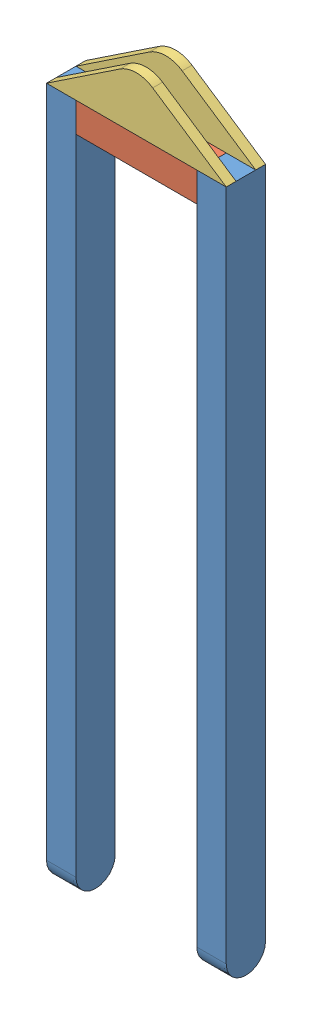
SolidWorks assembly stelaz spaw, configuration Domyślna. Lengths in mm.
Overall size (183 755 40).
5 component instances, 3 part files, 12 mates.
Components (placement in the parent):
- belka długa-1: belka długa [Domyślna] at (-439.7874 -5.7608 685) x (0 0 1) z (-1 0 0) size (40 700 30)
- belka długa-2: belka długa [Domyślna] at (-622.7874 -5.7608 725) x (0 0 -1) z (1 0 0) size (40 700 30)
- belka krótka-1: belka krótka [Domyślna] at (-592.7874 -35.7608 685) size (123 30 40)
- ucho stelaza-1: ucho stelaza [Domyślna] at (-622.7874 -5.7608 715) size (183 55 10)
- ucho stelaza-2: ucho stelaza [Domyślna] at (-622.7874 -5.7608 685) size (183 55 10)
Mates (geometry in assembly coordinates):
- Wspólnie13: coincident anti-aligned: plane of belka długa-2 through (-592.7874 -685.7608 705) normal (1 0 0); plane of belka krótka-1 through (-592.7874 -35.7608 725) normal (-1 0 0)
- Wspólnie14: coincident aligned: plane of belka długa-2 through (-592.7874 -5.7608 725) normal (0 0 1); plane of belka krótka-1 through (-592.7874 -35.7608 725) normal (0 0 1)
- Wspólnie15: coincident aligned: plane of belka długa-2 through (-592.7874 -5.7608 725) normal (0 1 0); plane of belka krótka-1 through (-592.7874 -5.7608 725) normal (0 1 0)
- Wspólnie16: coincident anti-aligned: plane of belka długa-1 through (-469.7874 -685.7608 705) normal (-1 0 0); plane of belka krótka-1 through (-469.7874 -35.7608 725) normal (1 0 0)
- Wspólnie17: coincident aligned: plane of belka długa-1 through (-469.7874 -5.7608 725) normal (0 0 1); plane of belka krótka-1 through (-592.7874 -35.7608 725) normal (0 0 1)
- Wspólnie18: coincident aligned: plane of belka długa-1 through (-469.7874 -5.7608 685) normal (0 1 0); plane of belka krótka-1 through (-592.7874 -5.7608 725) normal (0 1 0)
- Wspólnie20: coincident aligned: plane of belka krótka-1 through (-592.7874 -35.7608 725) normal (0 0 1); plane of ucho stelaza-1 through (-531.2874 19.2392 725) normal (0 0 1)
- Wspólnie22: coincident anti-aligned: plane of belka krótka-1 through (-592.7874 -5.7608 725) normal (0 1 0); plane of ucho stelaza-1 through (-622.7874 -5.7608 725) normal (0 -1 0)
- Wspólnie23: coincident anti-aligned: line of belka długa-2 through (-622.7874 -5.7608 685) axis (0 0 1); line of ucho stelaza-1 through (-622.7874 -5.7608 725) axis (0 0 -1)
- Wspólnie24: coincident: line of belka krótka-1 through (-469.7874 -5.7608 685) axis (-1 0 0); plane of ucho stelaza-2 through (-531.2874 19.2392 685) normal (0 0 -1)
- Wspólnie25: coincident anti-aligned: plane of belka krótka-1 through (-592.7874 -5.7608 725) normal (0 1 0); plane of ucho stelaza-2 through (-622.7874 -5.7608 695) normal (0 -1 0)
- Wspólnie26: coincident anti-aligned: line of belka długa-2 through (-622.7874 -5.7608 685) axis (0 0 1); line of ucho stelaza-2 through (-622.7874 -5.7608 695) axis (0 0 -1)
